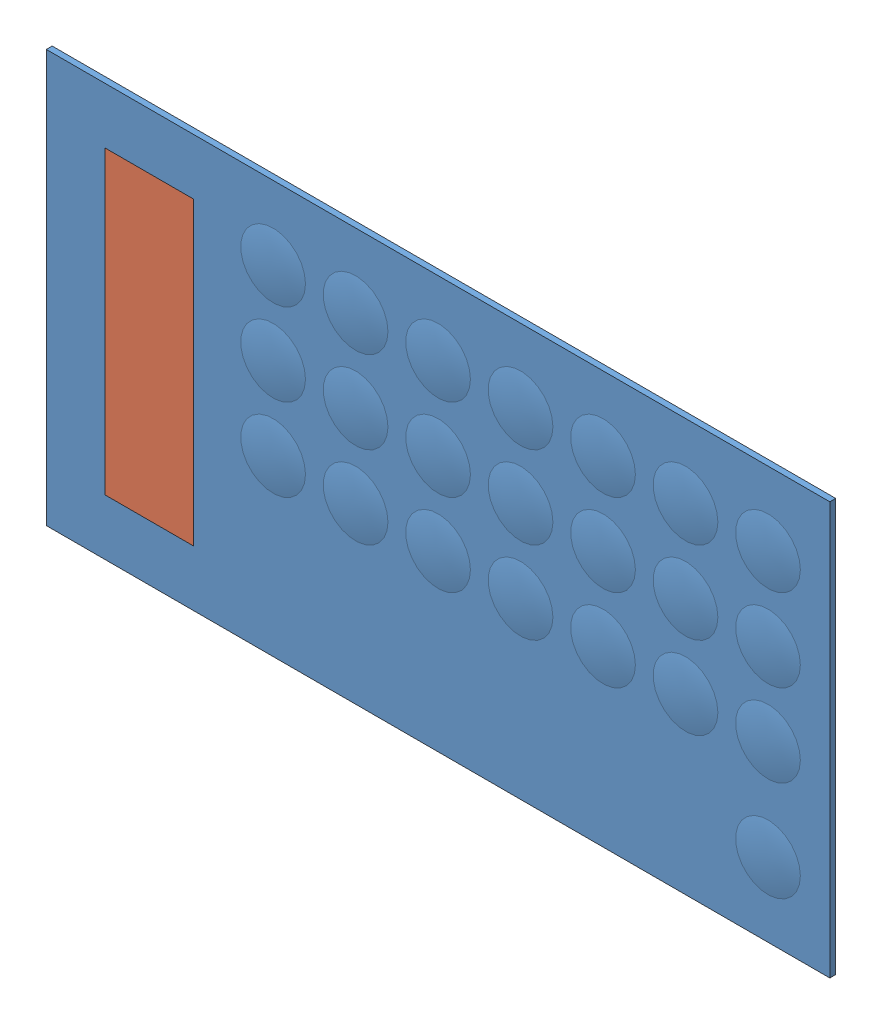
SolidWorks assembly Keyboard, configuration Domyślna. Lengths in mm.
Overall size (133 70 15.6).
3 component instances, 3 part files, 12 mates.
Components (placement in the parent):
- KeyboardBase^Keyboard-1: KeyboardBase^Keyboard [Domyślna] at origin size (133 70 1.5) (virtual)
- Window^Keyboard-1: Window^Keyboard [Domyślna] x (-1 0 0) z (0 0 -1) size (18 59 3) (virtual)
- Connector^Keyboard-3: Connector^Keyboard [Domyślna] at (-314.4504 25.6805 -11.1) x (1 0 0) z (0 0 -1) size (28 16 3) (virtual)
Mates (geometry in assembly coordinates):
- InPlace1: in place: plane of KeyboardBase^Keyboard-1 through (0 0 0) normal (0 0 1); moOrthogonalPlaneRef_w of KeyboardBase^Keyboard-1 through (0 0 0) normal (0 1 0); plane of KeyboardBase^Keyboard-1 through (0 0 0) normal (1 0 0); unknown of KeyboardBase^Keyboard-1
- Coincident1: coincident aligned: 
- Coincident2: coincident aligned: plane of KeyboardBase^Keyboard-1 through (0 0 0) normal (0 1 0)
- Coincident3: coincident anti-aligned: plane of KeyboardBase^Keyboard-1 through (0 0 0) normal (1 0 0)
- InPlace2: in place: plane of KeyboardBase^Keyboard-1 through (0 0 0) normal (0 0 -1); plane of Window^Keyboard-1 through (0 0 0) normal (0 0 -1); plane of KeyboardBase^Keyboard-1 through (0 0 0) normal (0 0 -1); plane of Window^Keyboard-1 through (0 0 0) normal (0 1 0); plane of KeyboardBase^Keyboard-1 through (0 0 0) normal (0 0 -1); plane of Window^Keyboard-1 through (0 0 0) normal (-1 0 0); plane of KeyboardBase^Keyboard-1 through (0 0 0) normal (0 0 -1); unknown of Window^Keyboard-1
- Coincident4: coincident aligned: plane of ?; plane of ?
- Coincident5: coincident aligned: moOrthogonalPlaneRef_w of KeyboardBase^Keyboard-1 through (0 0 0) normal (0 1 0); plane of Part9^Keyboard-1 through (0 0 0) normal (0 1 0)
- Coincident6: coincident anti-aligned: moOrthogonalPlaneRef_w of KeyboardBase^Keyboard-1 through (0 0 0) normal (1 0 0); plane of Part9^Keyboard-1 through (0 0 0) normal (-1 0 0)
- InPlace3: in place: plane of ? through (7.6 -32.8 -11.1) normal (0 0 -1); plane of ? through (0 0 -11.1) normal (0 0 -1); plane of ? through (7.6 -32.8 -11.1) normal (0 0 -1); plane of ? through (0 0 -11.1) normal (0 1 0); plane of ? through (7.6 -32.8 -11.1) normal (0 0 -1); plane of ? through (0 0 -11.1) normal (-1 0 0); plane of Connector^Keyboard-3 through (-314.4504 25.6805 -11.1) normal (0 0 -1); unknown of ?
- Coincident1: coincident aligned: plane of ?; plane of assembly
- Coincident2: coincident aligned: plane of Part86^Keyboard-1 through (-314.4504 25.6805 -11.1) normal (0 -1 0); moOrthogonalPlaneRef_w of DisplayBoard^Mantra-1/DisplayBoardV2-1 through (-314.4504 25.6805 -11.1) normal (0 -1 0)
- Coincident3: coincident anti-aligned: plane of Part86^Keyboard-1 through (-314.4504 25.6805 -11.1) normal (1 0 0); moOrthogonalPlaneRef_w of DisplayBoard^Mantra-1/DisplayBoardV2-1 through (-314.4504 25.6805 -11.1) normal (-1 0 0)
